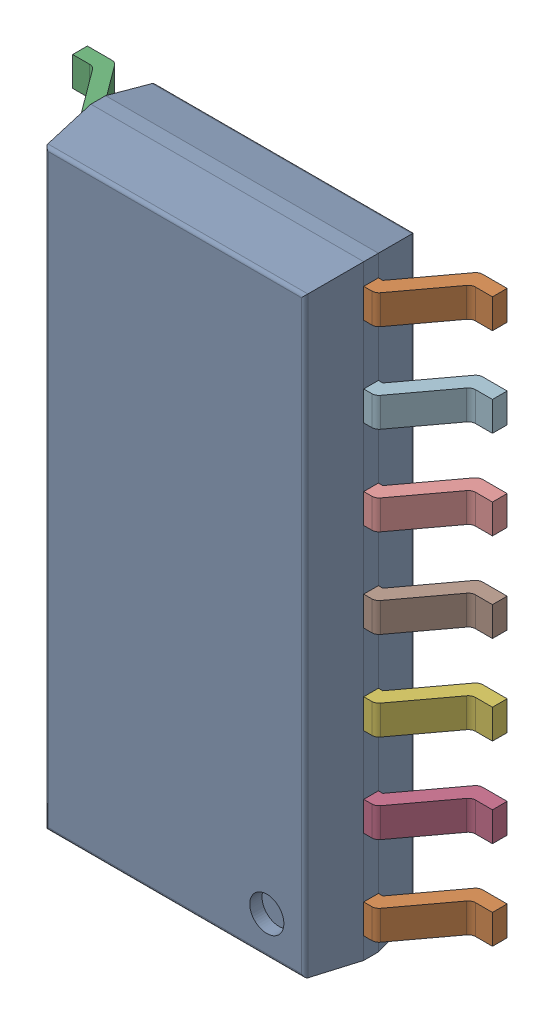
SolidWorks assembly IC11_IC103_1.step, configuration Default. Lengths in mm.
Overall size (6 8.65 1.75).
3 component instances, 2 part files, 0 mates.
Components (placement in the parent):
- 6348793888_1.step-3: 6348793888_1.step [Default] at (488.13 251.303 0) x (-1 0 0) z (0 0 1) size (6 8.65 1.75)
  - Body-16_1.step-14: Body-16_1.step [Default] at origin size (3.9 8.65 1.57)
  - PinsArrayLR-17_1.step-14: PinsArrayLR-17_1.step [Default] at origin size (6 8.04 1)
